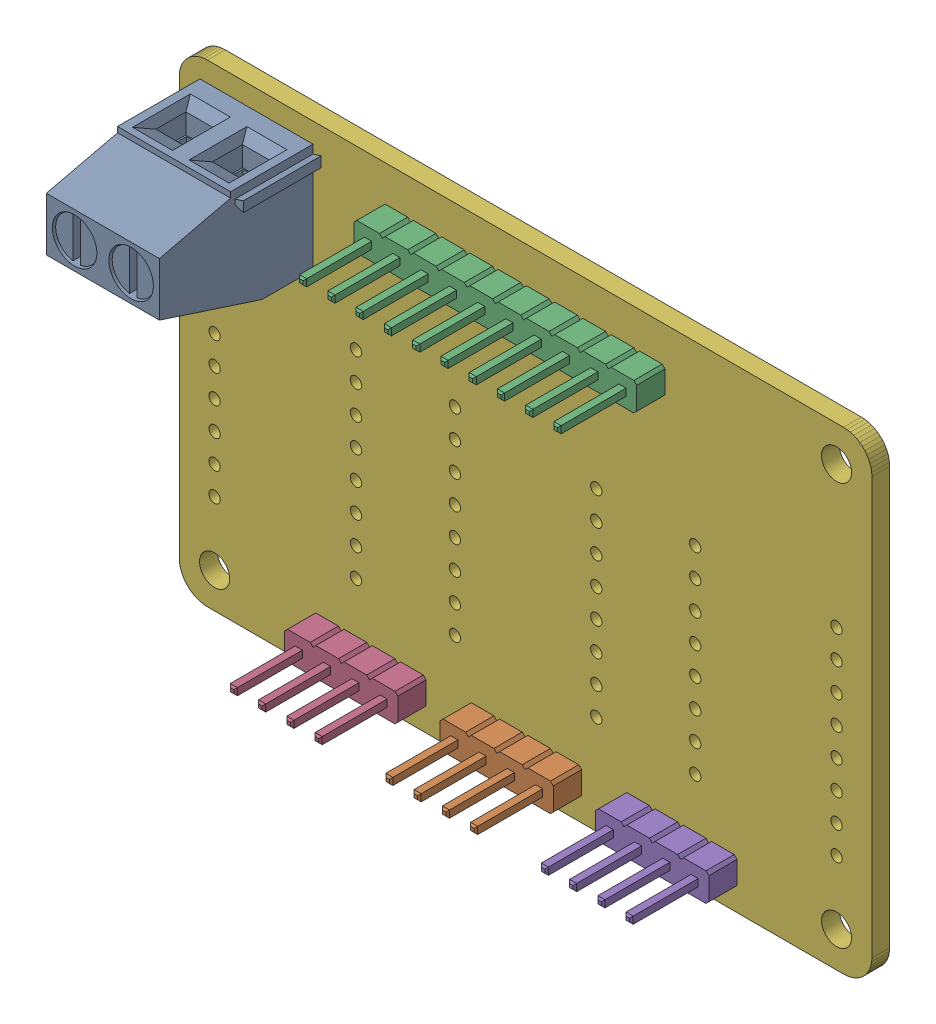
SolidWorks assembly PCB_V2, configuration Défaut. Lengths in mm.
Overall size (62.23 42.55 17.3).
11 component instances, 4 part files, 0 mates.
Components (placement in the parent):
- TerminalBlock_Phoenix_MKDS-1,5-2-5.08_1x02_P5.08mm_Horizontal-1: TerminalBlock_Phoenix_MKDS-1,5-2-5.08_1x02_P5.08mm_Horizontal [Défaut] at (178.435 -37.465 1.65) x (-1 0 0) z (0 0 1) size (10.9 9.8 17.3)
  - SOLID-0-1: SOLID-0 [Défaut] at origin size (10.9 9.8 17.3)
- PinHeader_1x04_P2.54mm_Vertical-1: PinHeader_1x04_P2.54mm_Vertical [Défaut] at (196.215 -70.485 1.65) x (0 1 0) z (0 0 1) size (2.54 10.16 11.54)
  - SOLID-1-1: SOLID-1 [Défaut] at origin size (2.54 10.16 11.54)
- PinHeader_1x10_P2.54mm_Vertical-1: PinHeader_1x10_P2.54mm_Vertical [Défaut] at (188.468 -35.56 1.65) x (0 1 0) z (0 0 1) size (2.54 25.4 11.54)
  - SOLID-2-1: SOLID-2 [Défaut] at origin size (2.54 25.4 11.54)
- PinHeader_1x04_P2.54mm_Vertical-2: PinHeader_1x04_P2.54mm_Vertical [Défaut] at (182.245 -70.485 1.65) x (0 1 0) z (0 0 1) size (2.54 10.16 11.54)
  - SOLID-1-1: SOLID-1 [Défaut] at origin size (2.54 10.16 11.54)
- PinHeader_1x04_P2.54mm_Vertical-3: PinHeader_1x04_P2.54mm_Vertical [Défaut] at (210.185 -70.485 1.65) x (0 1 0) z (0 0 1) size (2.54 10.16 11.54)
  - SOLID-1-1: SOLID-1 [Défaut] at origin size (2.54 10.16 11.54)
- PCB_V2 PCB2-1: PCB_V2 PCB2 [Défaut] at origin size (62.23 42.55 1.6)
